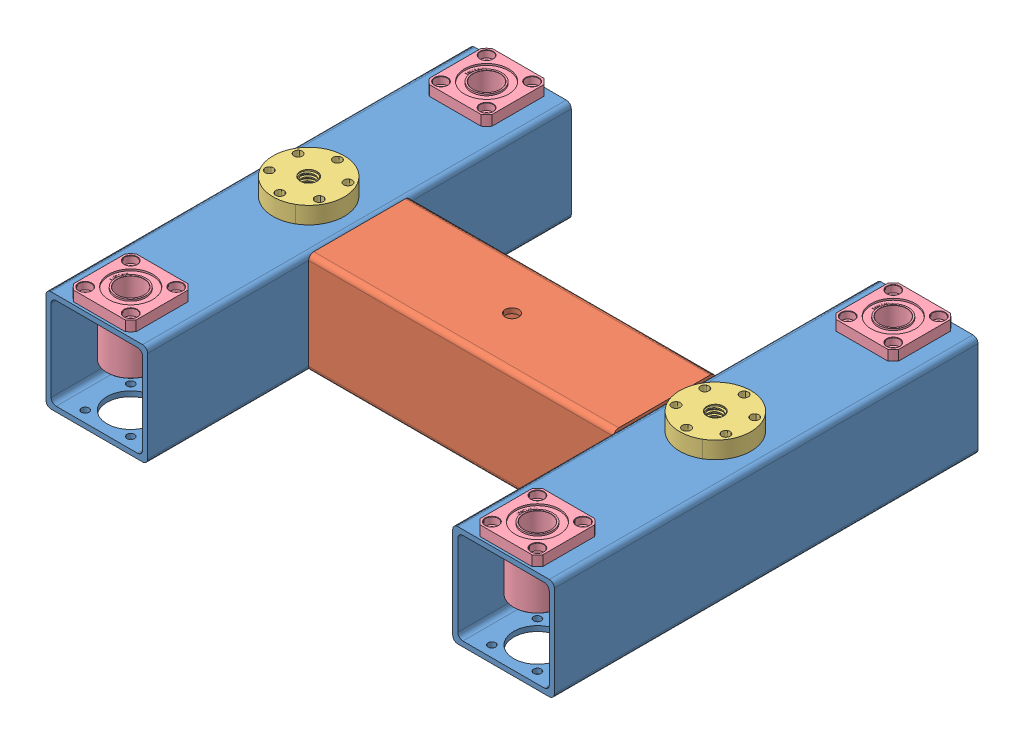
SolidWorks assembly moving_frame, configuration Domyślna. Lengths in mm.
Overall size (307.88 70 277.88).
9 component instances, 4 part files, 24 mates.
Components (placement in the parent):
- profile_60x60x3-1: profile_60x60x3 [Domyślna] at (1.1192 25.5119 92.8006) size (60 60 250)
- profile_60x60x3-2: profile_60x60x3 [Domyślna] at (241.1192 25.5119 92.8006) size (60 60 250)
- profile_60x60x3_1-1: profile_60x60x3_1 [Domyślna] at (211.1192 25.5119 217.8006) x (0 0 1) z (-1 0 0) size (60 60 180)
- tr10x2.step-2: tr10x2.step [Domyślna] at (1.1192 65.5119 217.8006) x (0 -1 0) z (0.5 0 0.866025) size (25.01 42 42)
- tr10x2.step-3: tr10x2.step [Domyślna] at (241.1192 65.5119 217.8006) x (0 -1 0) z (0.5 0 0.866025) size (25.01 42 42)
- LMK16UU-1: LMK16UU [Default] at (241.1192 61.5119 322.8006) x (0.707107 0 0.707107) z (0 -1 0) size (48 48 37)
- LMK16UU-2: LMK16UU [Default] at (241.1192 61.5119 112.8006) x (0.707107 0 0.707107) z (0 -1 0) size (48 48 37)
- LMK16UU-3: LMK16UU [Default] at (1.1192 61.5119 112.8006) x (0.707107 0 0.707107) z (0 -1 0) size (48 48 37)
- LMK16UU-4: LMK16UU [Default] at (1.1192 61.5119 322.8006) x (0.707107 0 0.707107) z (0 -1 0) size (48 48 37)
Mates (geometry in assembly coordinates):
- Coincident1: coincident aligned: plane of profile_60x60x3-1 through (1.1192 25.5119 342.8006) normal (0 0 1); plane of profile_60x60x3-2 through (241.1192 25.5119 342.8006) normal (0 0 1)
- Coincident2: coincident aligned: plane of profile_60x60x3-1 through (-28.8808 55.5119 342.8006) normal (0 1 0); plane of profile_60x60x3-2 through (211.1192 55.5119 342.8006) normal (0 1 0)
- Coincident3: coincident anti-aligned: plane of profile_60x60x3-1 through (31.1192 55.5119 342.8006) normal (1 0 0); plane of profile_60x60x3_1-1 through (31.1192 25.5119 217.8006) normal (-1 0 0)
- Coincident4: coincident aligned: plane of profile_60x60x3-1 through (-28.8808 55.5119 342.8006) normal (0 1 0); plane of profile_60x60x3_1-1 through (31.1192 55.5119 187.8006) normal (0 1 0)
- Coincident5: coincident anti-aligned: plane of profile_60x60x3-2 through (211.1192 55.5119 342.8006) normal (-1 0 0); plane of profile_60x60x3_1-1 through (211.1192 25.5119 217.8006) normal (1 0 0)
- Distance1: distance = 95 mm aligned: plane of profile_60x60x3_1-1 through (31.1192 55.5119 247.8006) normal (0 0 1); plane of profile_60x60x3-2 through (241.1192 25.5119 342.8006) normal (0 0 1)
- Concentric1: concentric anti-aligned: cylinder of profile_60x60x3-1 through (-13.6032 55.5119 209.3006) axis (0 -1 0) radius 2; cylinder of tr10x2.step-2 through (-13.6032 48.4409 209.3006) axis (0 1 0) radius 2.5
- Concentric2: concentric anti-aligned: cylinder of profile_60x60x3-1 through (1.1192 55.5119 200.8006) axis (0 -1 0) radius 2; cylinder of tr10x2.step-2 through (1.1192 48.4409 200.8006) axis (0 1 0) radius 2.5
- Coincident7: coincident anti-aligned: plane of profile_60x60x3-1 through (-28.8808 55.5119 342.8006) normal (0 1 0); plane of tr10x2.step-2 through (1.1192 55.5119 217.8006) normal (0 -1 0)
- Concentric3: concentric anti-aligned: cylinder of profile_60x60x3-2 through (255.8416 55.5119 209.3006) axis (0 -1 0) radius 2; cylinder of tr10x2.step-3 through (255.8416 48.4409 209.3006) axis (0 1 0) radius 2.5
- Concentric4: concentric anti-aligned: cylinder of profile_60x60x3-2 through (241.1192 55.5119 200.8006) axis (0 -1 0) radius 2; cylinder of tr10x2.step-3 through (241.1192 48.4409 200.8006) axis (0 1 0) radius 2.5
- Coincident8: coincident anti-aligned: plane of profile_60x60x3-2 through (211.1192 55.5119 342.8006) normal (0 1 0); plane of tr10x2.step-3 through (241.1192 55.5119 217.8006) normal (0 -1 0)
- Coincident9: coincident anti-aligned: cylinder of profile_60x60x3-2 through (227.6842 55.5119 336.2356) axis (0 -1 0) radius 2.25; circle of LMK16UU-1
- Concentric5: concentric anti-aligned: cylinder of profile_60x60x3-2 through (254.5542 55.5119 309.3656) axis (0 -1 0) radius 2.25; cylinder of LMK16UU-1 through (254.5542 49.148 309.3656) axis (0 1 0) radius 2.25
- Coincident11: coincident anti-aligned: plane of profile_60x60x3-1 through (-28.8808 55.5119 342.8006) normal (0 1 0); plane of LMK16UU-1 through (241.1192 55.5119 322.8006) normal (0 -1 0)
- Concentric6: concentric anti-aligned: cylinder of profile_60x60x3-2 through (254.5542 55.5119 126.2356) axis (0 -1 0) radius 2.25; cylinder of LMK16UU-2 through (254.5542 57.4119 126.2356) axis (0 1 0) radius 3.75
- Concentric7: concentric anti-aligned: cylinder of profile_60x60x3-2 through (227.6842 55.5119 99.3656) axis (0 -1 0) radius 2.25; cylinder of LMK16UU-2 through (227.6842 57.4119 99.3656) axis (0 1 0) radius 3.75
- Coincident12: coincident anti-aligned: plane of profile_60x60x3-2 through (211.1192 55.5119 342.8006) normal (0 1 0); plane of LMK16UU-2 through (241.1192 55.5119 112.8006) normal (0 -1 0)
- Concentric8: concentric anti-aligned: cylinder of profile_60x60x3-1 through (14.5542 55.5119 126.2356) axis (0 -1 0) radius 2.25; cylinder of LMK16UU-3 through (14.5542 57.4119 126.2356) axis (0 1 0) radius 3.75
- Concentric9: concentric anti-aligned: cylinder of profile_60x60x3-1 through (-12.3158 55.5119 99.3656) axis (0 -1 0) radius 2.25; cylinder of LMK16UU-3 through (-12.3158 57.4119 99.3656) axis (0 1 0) radius 3.75
- Coincident13: coincident anti-aligned: plane of profile_60x60x3-1 through (-28.8808 55.5119 342.8006) normal (0 1 0); plane of LMK16UU-3 through (1.1192 55.5119 112.8006) normal (0 -1 0)
- Concentric10: concentric anti-aligned: cylinder of profile_60x60x3-1 through (14.5542 55.5119 336.2356) axis (0 -1 0) radius 2.25; cylinder of LMK16UU-4 through (14.5542 49.148 336.2356) axis (0 1 0) radius 2.25
- Concentric11: concentric anti-aligned: cylinder of profile_60x60x3-1 through (-12.3158 55.5119 309.3656) axis (0 -1 0) radius 2.25; cylinder of LMK16UU-4 through (-12.3158 49.148 309.3656) axis (0 1 0) radius 2.25
- Coincident14: coincident anti-aligned: plane of profile_60x60x3-1 through (-28.8808 55.5119 342.8006) normal (0 1 0); plane of LMK16UU-4 through (1.1192 55.5119 322.8006) normal (0 -1 0)
